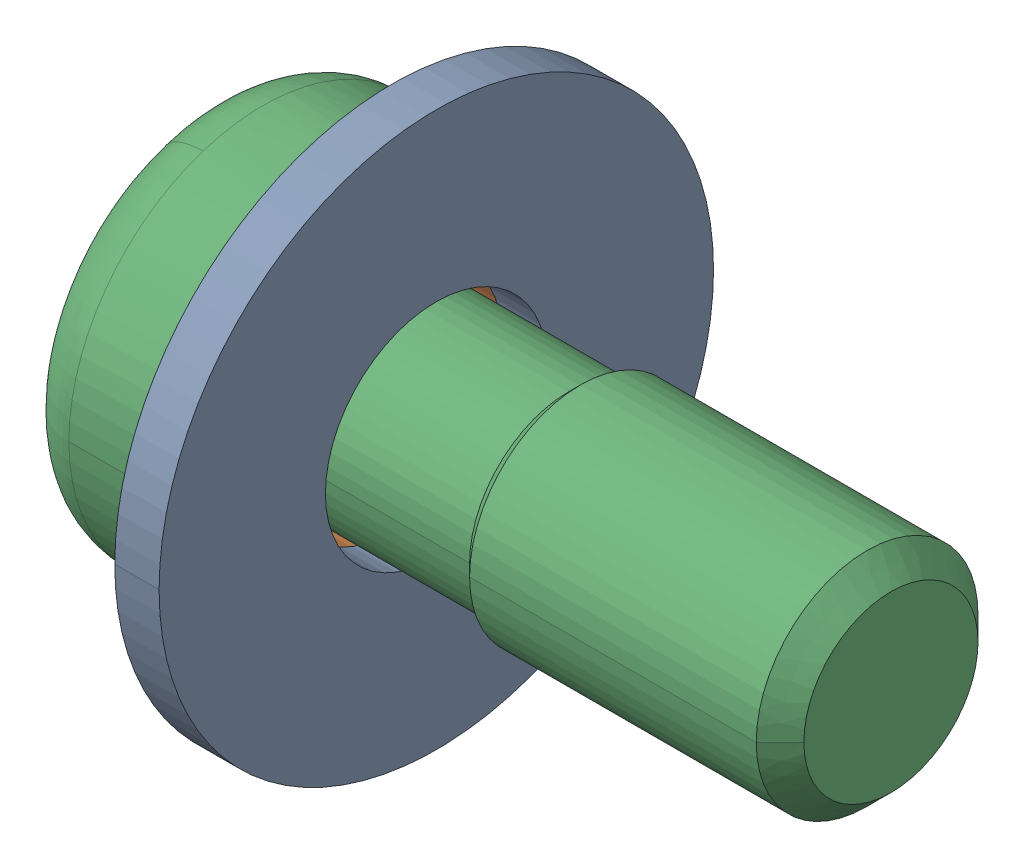
SolidWorks assembly SCBJ4_10, configuration Default. Lengths in mm.
Overall size (12.57 10 10).
3 component instances, 3 part files, 0 mates.
Components (placement in the parent):
- SCBJ4_10_3-1: SCBJ4_10_3 [Default] at (1.4 0 0) size (0.8 10 10)
- SCBJ4_10_5-1: SCBJ4_10_5 [Default] at (0.5 0 0) size (1 7 6.89)
- SCBJ4_10_7-1: SCBJ4_10_7 [Default] at origin size (12.57 7 7)
